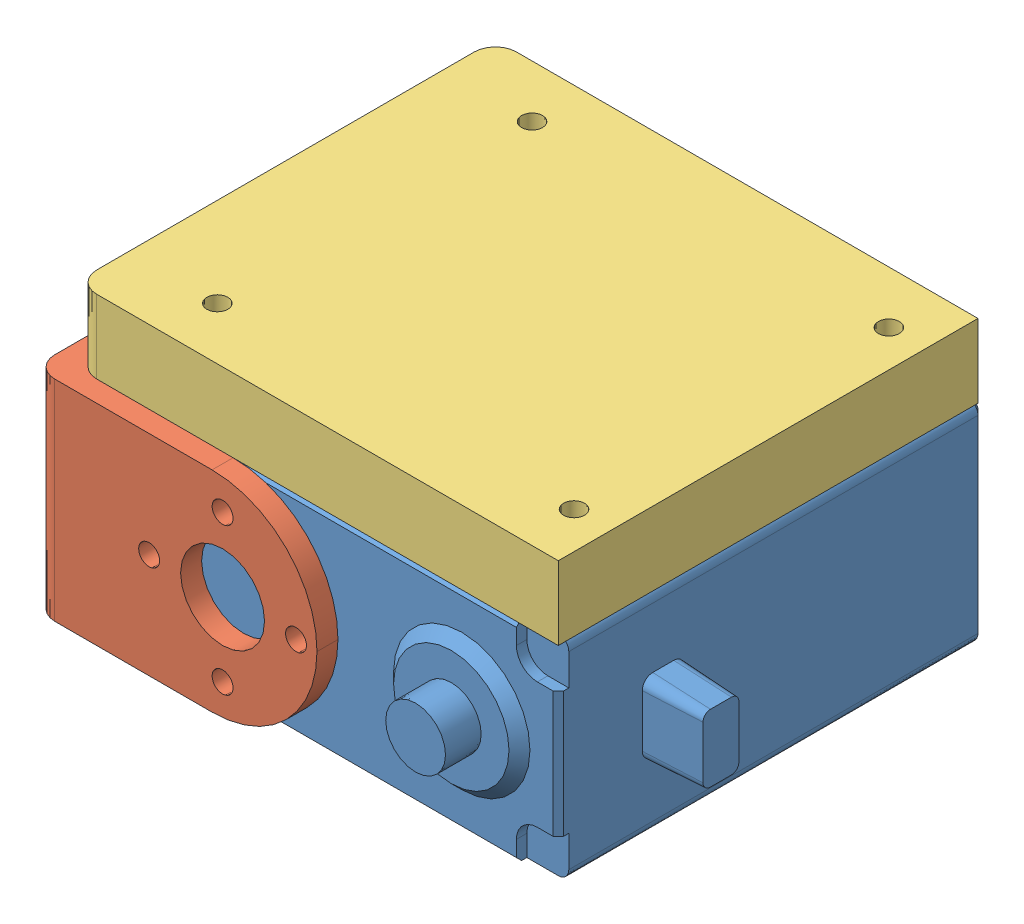
SolidWorks assembly moteur-complet, configuration Défaut. Lengths in mm.
Overall size (55.5 27 48.8).
11 component instances, 5 part files, 26 mates.
Components (placement in the parent):
- moteur-1: moteur [Défaut] at (-9.5825 -1.0731 48.8) size (45.5 20 48.8)
- moteur-support-fixe-1: moteur-support-fixe [Défaut] at (-5.7196 9.1116 15.94) x (1 0 0) z (0 -1 0) size (27.58 44 20)
- moteur_semelle-1: moteur_semelle [Défaut] at (-31.3007 -10.8884 28.8) x (-1 0 0) z (0 0 1) size (48 27 40)
- ecrou-h-1: ecrou-h [6007 HU M2] at (-27.7007 -5.8884 23.8) x (0 0.5 -0.866025) z (0 -0.866025 -0.5) size (4 1.6 4.62)
- ecrou-h-2: ecrou-h [6007 HU M2] at (-27.7007 -5.8884 33.8) x (0 -0.5 -0.866025) z (0 -0.866025 0.5) size (4 1.6 4.62)
- ecrou-h-3: ecrou-h [6007 HU M2] at (-27.7007 4.1116 33.8) x (0 -0.5 -0.866025) z (0 -0.866025 0.5) size (4 1.6 4.62)
- ecrou-h-4: ecrou-h [6007 HU M2] at (-27.7007 4.1116 23.8) x (0 -1 0) z (0 0 1) size (4 1.6 4.62)
- vis-chc-1: vis-chc [Vis CHC M2x6] at (-33.3007 -5.8884 33.8) x (0 -0.454411 0.890792) z (0 -0.890792 -0.454411) size (3.8 8 3.8)
- vis-chc-2: vis-chc [Vis CHC M2x6] at (-33.3007 4.1116 33.8) x (0 -0.381849 0.924225) z (0 -0.924225 -0.381849) size (3.8 8 3.8)
- vis-chc-3: vis-chc [Vis CHC M2x6] at (-33.3007 4.1116 23.8) x (0 -0.381849 0.924225) z (0 -0.924225 -0.381849) size (3.8 8 3.8)
- vis-chc-4: vis-chc [Vis CHC M2x6] at (-33.3007 -5.8884 23.8) x (0 -0.381849 0.924225) z (0 -0.924225 -0.381849) size (3.8 8 3.8)
Mates (geometry in assembly coordinates):
- Coaxiale12: concentric aligned: cylinder of moteur-1 through (-22.3007 -0.8884 43.8) axis (0 0 1) radius 0.79; cylinder of moteur-support-fixe-1 through (-22.3007 -0.8884 6.799) axis (0 0 1) radius 1
- Coaxiale13: concentric aligned: cylinder of moteur-1 through (-15.3007 -7.8884 43.8) axis (0 0 1) radius 0.79; cylinder of moteur-support-fixe-1 through (-15.3007 -7.8884 6.799) axis (0 0 1) radius 1
- Coïncidente2: coincident anti-aligned: plane of moteur-1 through (-9.5825 -1.0731 48.8) normal (0 0 1); plane of moteur-support-fixe-1 through (-29.3007 -10.8884 48.8) normal (0 0 -1)
- Coïncidente3: coincident anti-aligned: plane of moteur-support-fixe-1 through (-31.3007 -10.8884 10.8) normal (1 0 0); plane of moteur_semelle-1 through (-31.3007 16.1116 8.8) normal (-1 0 0)
- Coïncidente5: coincident anti-aligned: plane of moteur-1 through (-25.3007 9.1116 8.3) normal (0 1 0); plane of moteur_semelle-1 through (14.6993 9.1116 48.8) normal (0 -1 0)
- Coaxiale14: concentric anti-aligned: cylinder of moteur-support-fixe-1 through (-5.7186 -0.8884 28.8) axis (-1 0 0) radius 3; cylinder of moteur_semelle-1 through (-33.3007 -0.8884 28.8) axis (1 0 0) radius 2.9
- Coaxiale15: concentric anti-aligned: cylinder of moteur_semelle-1 through (14.7003 -5.8884 23.8) axis (-1 0 0) radius 1; cylinder of ecrou-h-m2-1 through (-29.3007 -5.8884 23.8) axis (1 0 0) radius 0.7835
- Parallèle2: parallel anti-aligned: plane of moteur_semelle-1 through (-29.3007 -7.9063 24.965) normal (0 1 0); plane of ecrou-h-m2-1 through (-29.3007 -7.8884 24.9547) normal (0 -1 0)
- Coïncidente9: coincident anti-aligned: plane of moteur_semelle-1 through (-29.3007 -10.8884 28.8) normal (1 0 0); plane of ecrou-h-m2-1 through (-29.3007 -3.8884 22.6453) normal (-1 0 0)
- Coaxiale16: concentric anti-aligned: cylinder of moteur_semelle-1 through (14.7003 4.1116 33.8) axis (-1 0 0) radius 1; cylinder of ecrou-h-m2-3 through (-29.3007 4.1116 33.8) axis (1 0 0) radius 0.7835
- Coaxiale17: concentric anti-aligned: cylinder of moteur_semelle-1 through (14.7003 4.1116 23.8) axis (-1 0 0) radius 1; cylinder of ecrou-h-m2-4 through (-29.3007 4.1116 23.8) axis (1 0 0) radius 0.7835
- Coaxiale18: concentric anti-aligned: cylinder of moteur_semelle-1 through (14.7003 -5.8884 33.8) axis (-1 0 0) radius 1; cylinder of ecrou-h-m2-2 through (-29.3007 -5.8884 33.8) axis (1 0 0) radius 0.7835
- Parallèle3: parallel anti-aligned: plane of moteur_semelle-1 through (-29.3007 -7.9063 34.965) normal (0 1 0); plane of ecrou-h-m2-2 through (-29.3007 -7.8884 34.9547) normal (0 -1 0)
- Coïncidente11: coincident anti-aligned: plane of moteur_semelle-1 through (-29.3007 -10.8884 28.8) normal (1 0 0); plane of ecrou-h-m2-2 through (-29.3007 -5.8884 31.4906) normal (-1 0 0)
- Parallèle4: parallel anti-aligned: plane of moteur_semelle-1 through (-29.3007 2.0937 24.965) normal (0 1 0); plane of ecrou-h-m2-4 through (-29.3007 2.1116 24.9547) normal (0 -1 0)
- Coïncidente13: coincident anti-aligned: plane of moteur_semelle-1 through (-29.3007 -10.8884 28.8) normal (1 0 0); plane of ecrou-h-m2-4 through (-29.3007 2.1116 22.6453) normal (-1 0 0)
- Parallèle5: parallel anti-aligned: plane of moteur_semelle-1 through (-29.3007 2.0937 34.965) normal (0 1 0); plane of ecrou-h-m2-3 through (-29.3007 2.1116 34.9547) normal (0 -1 0)
- Coïncidente15: coincident anti-aligned: plane of moteur_semelle-1 through (-29.3007 -10.8884 28.8) normal (1 0 0); plane of ecrou-h-m2-3 through (-29.3007 4.1116 31.4906) normal (-1 0 0)
- Coaxiale20: concentric aligned: cylinder of moteur-support-fixe-1 through (-5.7186 -5.8884 33.8) axis (-1 0 0) radius 1.5; cylinder of vis-chc-m2x5-1 through (-27.3007 -5.8884 33.8) axis (-1 0 0) radius 1
- Coaxiale21: concentric aligned: cylinder of moteur-support-fixe-1 through (-5.7186 -5.8884 23.8) axis (-1 0 0) radius 1.5; cylinder of vis-chc-m2x5-4 through (-27.3007 -5.8884 23.8) axis (-1 0 0) radius 1
- Coaxiale22: concentric aligned: cylinder of moteur-support-fixe-1 through (-5.7186 4.1116 23.8) axis (-1 0 0) radius 1.5; cylinder of vis-chc-m2x5-3 through (-27.3007 4.1116 23.8) axis (-1 0 0) radius 1
- Coaxiale23: concentric aligned: cylinder of moteur-support-fixe-1 through (-5.7186 4.1116 33.8) axis (-1 0 0) radius 1.5; cylinder of vis-chc-m2x5-2 through (-27.3007 4.1116 33.8) axis (-1 0 0) radius 1
- Coïncidente18: coincident anti-aligned: plane of moteur-support-fixe-1 through (-33.3007 -10.8884 48.8) normal (-1 0 0); plane of vis-chc-m2x5-2 through (-33.3007 4.1116 33.8) normal (1 0 0)
- Coïncidente19: coincident anti-aligned: plane of moteur-support-fixe-1 through (-33.3007 -10.8884 48.8) normal (-1 0 0); plane of vis-chc-m2x5-3 through (-33.3007 4.1116 23.8) normal (1 0 0)
- Coïncidente20: coincident anti-aligned: plane of moteur-support-fixe-1 through (-33.3007 -10.8884 48.8) normal (-1 0 0); plane of vis-chc-m2x5-1 through (-33.3007 -5.8884 33.8) normal (1 0 0)
- Coïncidente21: coincident anti-aligned: plane of moteur-support-fixe-1 through (-33.3007 -10.8884 48.8) normal (-1 0 0); plane of vis-chc-m2x5-4 through (-33.3007 -5.8884 23.8) normal (1 0 0)
